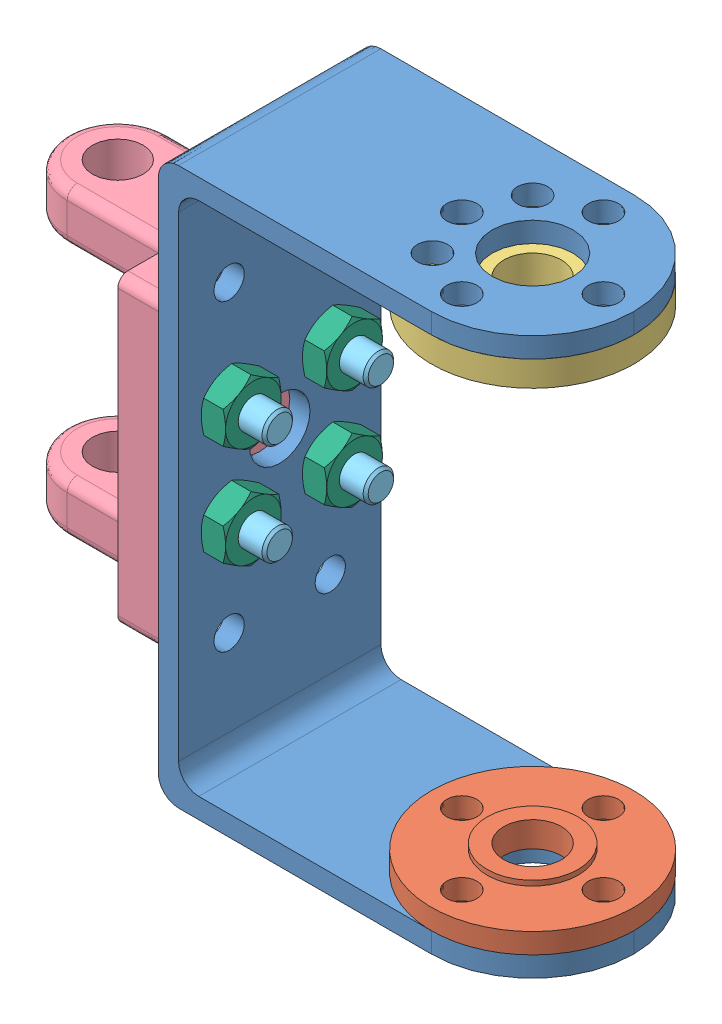
SolidWorks assembly moteur-bras-v2, configuration Défaut. Lengths in mm.
Overall size (56 55 20).
12 component instances, 6 part files, 28 mates.
Components (placement in the parent):
- moteur-support-mobile-v2-1: moteur-support-mobile-v2 [Défaut] at (18.386 -2.2808 45) size (37 55 20)
- moteur-platine_libre-1: moteur-platine_libre [Défaut] at (8.386 -27.7808 55) x (1 0 0) z (0 1 0) size (20 20 2.5)
- moteur-platine_moteur-1: moteur-platine_moteur [Défaut] at (8.386 23.2192 55) x (1 0 0) z (0 -1 0) size (20 20 4.5)
- support-fourchette-chc_m3-1: support-fourchette-chc_m3 [Défaut] at (-32.614 -2.2808 55) x (0 1 0) z (0 0 1) size (30 19 20)
- vis-chc-1: vis-chc [Vis CHC M3x8] at (-19.614 2.7192 50) x (0 0.164744 0.986336) z (0 -0.986336 0.164744) size (5.5 11 5.5)
- ecrou-h-1: ecrou-h [6012 HU M3] at (-16.614 2.7192 50) x (0 0.866025 0.5) z (0 -0.5 0.866025) size (5.5 2.4 6.35)
- ecrou-h-2: ecrou-h [6012 HU M3] at (-14.214 2.7192 60) x (0 -0.866025 -0.5) z (0 -0.5 0.866025) size (5.5 2.4 6.35)
- ecrou-h-3: ecrou-h [6012 HU M3] at (-14.214 -7.2808 50) x (0 -0.866025 -0.5) z (0 -0.5 0.866025) size (5.5 2.4 6.35)
- ecrou-h-4: ecrou-h [6012 HU M3] at (-14.214 -7.2808 60) x (0 -0.866025 -0.5) z (0 -0.5 0.866025) size (5.5 2.4 6.35)
- vis-chc-2: vis-chc [Vis CHC M3x8] at (-19.614 2.7192 60) x (0 -0.933966 -0.357361) z (0 0.357361 -0.933966) size (5.5 11 5.5)
- vis-chc-3: vis-chc [Vis CHC M3x8] at (-19.614 -7.2808 60) x (0 0.351541 0.936173) z (0 -0.936173 0.351541) size (5.5 11 5.5)
- vis-chc-4: vis-chc [Vis CHC M3x8] at (-19.614 -7.2808 50) x (0 -0.47591 0.879494) z (0 -0.879494 -0.47591) size (5.5 11 5.5)
Mates (geometry in assembly coordinates):
- Coïncidente1: coincident anti-aligned: plane of moteur-support-mobile-v2-1 through (-14.614 23.2192 65) normal (0 -1 0); plane of moteur-platine_moteur-1 through (8.386 23.2192 55) normal (0 1 0)
- Coïncidente2: coincident anti-aligned: plane of moteur-support-mobile-v2-1 through (18.386 -27.7808 65) normal (0 1 0); plane of moteur-platine_libre-1 through (8.386 -27.7808 55) normal (0 -1 0)
- Coaxiale1: concentric aligned: cylinder of moteur-support-mobile-v2-1 through (1.386 -29.7808 55) axis (0 1 0) radius 1.5; cylinder of moteur-platine_libre-1 through (1.386 -27.7808 55) axis (0 1 0) radius 1.5
- Coaxiale2: concentric anti-aligned: cylinder of moteur-support-mobile-v2-1 through (8.386 -29.7808 55) axis (0 1 0) radius 4; cylinder of moteur-platine_libre-1 through (8.386 -25.7808 55) axis (0 -1 0) radius 2.85
- Coaxiale3: concentric aligned: cylinder of moteur-support-mobile-v2-1 through (8.386 -29.7808 55) axis (0 1 0) radius 4; cylinder of moteur-platine_moteur-1 through (8.386 20.7192 55) axis (0 1 0) radius 2.85
- Coaxiale4: concentric anti-aligned: cylinder of moteur-support-mobile-v2-1 through (8.386 -29.7808 62) axis (0 1 0) radius 1.5; cylinder of moteur-platine_moteur-1 through (8.386 23.2192 62) axis (0 -1 0) radius 1.5
- Coïncidente3: coincident anti-aligned: plane of moteur-support-mobile-v2-1 through (-18.614 23.2192 65) normal (-1 0 0); plane of support-fourchette-chc_m3-1 through (-18.614 -2.2808 55) normal (1 0 0)
- Coaxiale5: concentric aligned: cylinder of moteur-support-mobile-v2-1 through (18.387 2.7192 50) axis (-1 0 0) radius 1.5; cylinder of support-fourchette-chc_m3-1 through (-18.613 2.7192 50) axis (-1 0 0) radius 1.6
- Coaxiale6: concentric aligned: cylinder of support-fourchette-chc_m3-1 through (-18.613 2.7192 50) axis (-1 0 0) radius 1.6; cylinder of vis-chc-m2-1 through (-11.614 2.7192 50) axis (-1 0 0) radius 1.5
- Coïncidente4: coincident anti-aligned: plane of moteur-support-mobile-v2-1 through (-16.614 -25.7808 65) normal (1 0 0); plane of ecrou-h-m2-1 through (-16.614 5.8946 50) normal (-1 0 0)
- Coaxiale7: concentric aligned: cylinder of moteur-support-mobile-v2-1 through (18.387 2.7192 50) axis (-1 0 0) radius 1.5; cylinder of ecrou-h-m2-1 through (-14.214 2.7192 50) axis (-1 0 0) radius 1.2295
- Parallèle1: parallel aligned: plane of moteur-support-mobile-v2-1 through (-16.614 23.2192 45) normal (0 0 -1); plane of ecrou-h-m2-1 through (-14.214 4.3069 47.25) normal (0 0 -1)
- Coaxiale8: concentric aligned: cylinder of moteur-support-mobile-v2-1 through (18.387 2.7192 60) axis (-1 0 0) radius 1.5; cylinder of vis-chc-2 through (-11.614 2.7192 60) axis (-1 0 0) radius 1.5
- Coaxiale9: concentric aligned: cylinder of moteur-support-mobile-v2-1 through (18.387 -7.2808 60) axis (-1 0 0) radius 1.5; cylinder of vis-chc-3 through (-11.614 -7.2808 60) axis (-1 0 0) radius 1.5
- Coaxiale10: concentric aligned: cylinder of moteur-support-mobile-v2-1 through (18.387 -7.2808 50) axis (-1 0 0) radius 1.5; cylinder of vis-chc-4 through (-11.614 -7.2808 50) axis (-1 0 0) radius 1.5
- Coïncidente8: coincident anti-aligned: plane of support-fourchette-chc_m3-1 through (-19.614 2.7192 50) normal (-1 0 0); plane of vis-chc-1 through (-19.614 2.7192 50) normal (1 0 0)
- Coïncidente9: coincident anti-aligned: plane of support-fourchette-chc_m3-1 through (-19.614 2.7192 60) normal (-1 0 0); plane of vis-chc-2 through (-19.614 2.7192 60) normal (1 0 0)
- Coïncidente10: coincident anti-aligned: plane of support-fourchette-chc_m3-1 through (-19.614 -7.2808 60) normal (-1 0 0); plane of vis-chc-3 through (-19.614 -7.2808 60) normal (1 0 0)
- Coïncidente11: coincident anti-aligned: plane of support-fourchette-chc_m3-1 through (-19.614 -7.2808 50) normal (-1 0 0); plane of vis-chc-4 through (-19.614 -7.2808 50) normal (1 0 0)
- Coaxiale11: concentric anti-aligned: cylinder of ecrou-h-2 through (-16.614 2.7192 60) axis (1 0 0) radius 1.2295; cylinder of vis-chc-2 through (-11.614 2.7192 60) axis (-1 0 0) radius 1.5
- Coaxiale12: concentric anti-aligned: cylinder of ecrou-h-3 through (-16.614 -7.2808 50) axis (1 0 0) radius 1.2295; cylinder of vis-chc-4 through (-11.614 -7.2808 50) axis (-1 0 0) radius 1.5
- Coaxiale13: concentric anti-aligned: cylinder of ecrou-h-4 through (-16.614 -7.2808 60) axis (1 0 0) radius 1.2295; cylinder of vis-chc-3 through (-11.614 -7.2808 60) axis (-1 0 0) radius 1.5
- Coïncidente12: coincident anti-aligned: plane of moteur-support-mobile-v2-1 through (-16.614 -25.7808 65) normal (1 0 0); plane of ecrou-h-4 through (-16.614 -8.8685 57.25) normal (-1 0 0)
- Coïncidente13: coincident anti-aligned: plane of moteur-support-mobile-v2-1 through (-16.614 -25.7808 65) normal (1 0 0); plane of ecrou-h-3 through (-16.614 -8.8685 47.25) normal (-1 0 0)
- Coïncidente14: coincident anti-aligned: plane of moteur-support-mobile-v2-1 through (-16.614 -25.7808 65) normal (1 0 0); plane of ecrou-h-2 through (-16.614 1.1315 57.25) normal (-1 0 0)
- Parallèle2: parallel aligned: plane of moteur-support-mobile-v2-1 through (-16.614 23.2192 65) normal (0 0 1); plane of ecrou-h-2 through (-16.614 4.3069 62.75) normal (0 0 1)
- Parallèle3: parallel aligned: plane of moteur-support-mobile-v2-1 through (-16.614 23.2192 65) normal (0 0 1); plane of ecrou-h-4 through (-16.614 -5.6931 62.75) normal (0 0 1)
- Parallèle4: parallel aligned: plane of moteur-support-mobile-v2-1 through (-16.614 23.2192 45) normal (0 0 -1); plane of ecrou-h-3 through (-16.614 -8.8685 47.25) normal (0 0 -1)
